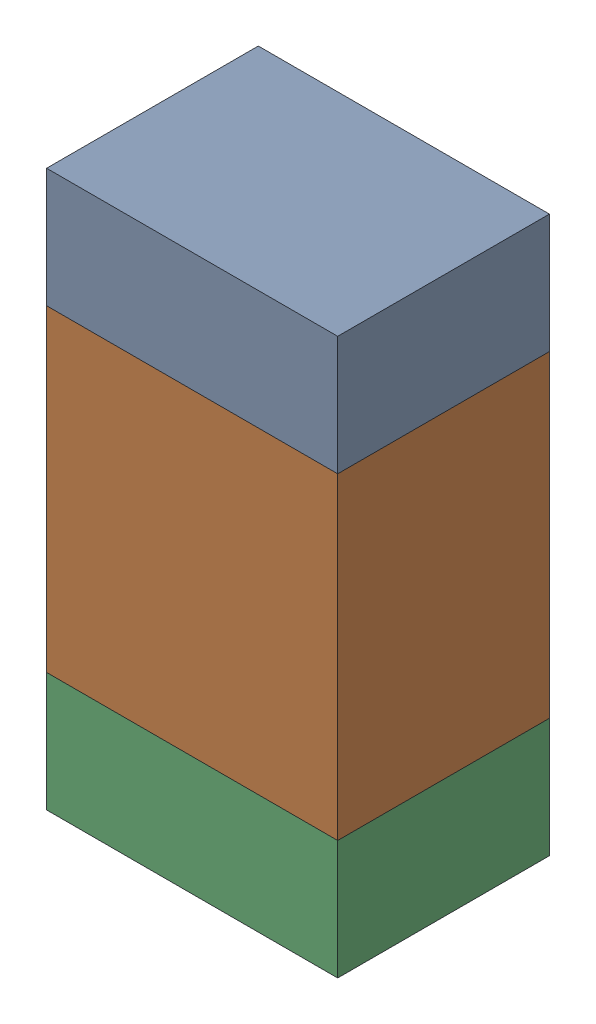
SolidWorks assembly R321_2PCB, configuration Default. Lengths in mm.
Overall size (0.55 1.05 0.4).
6 component instances, 2 part files, 0 mates.
Components (placement in the parent):
- 846483288-1: 846483288 [Default] at (134.4999 88.9124 -2.0638) size (0.55 0.22 0.4)
  - Extruded_12-1: Extruded_12 [Default] at origin size (0.55 0.22 0.4)
- 846483424-1: 846483424 [Default] at (134.4999 88.4999 -2.0638) size (0.55 0.6 0.4)
  - Extruded_13-1: Extruded_13 [Default] at origin size (0.55 0.6 0.4)
- 846483288-2: 846483288 [Default] at (134.4999 88.0874 -2.0638) size (0.55 0.22 0.4)
  - Extruded_12-1: Extruded_12 [Default] at origin size (0.55 0.22 0.4)
